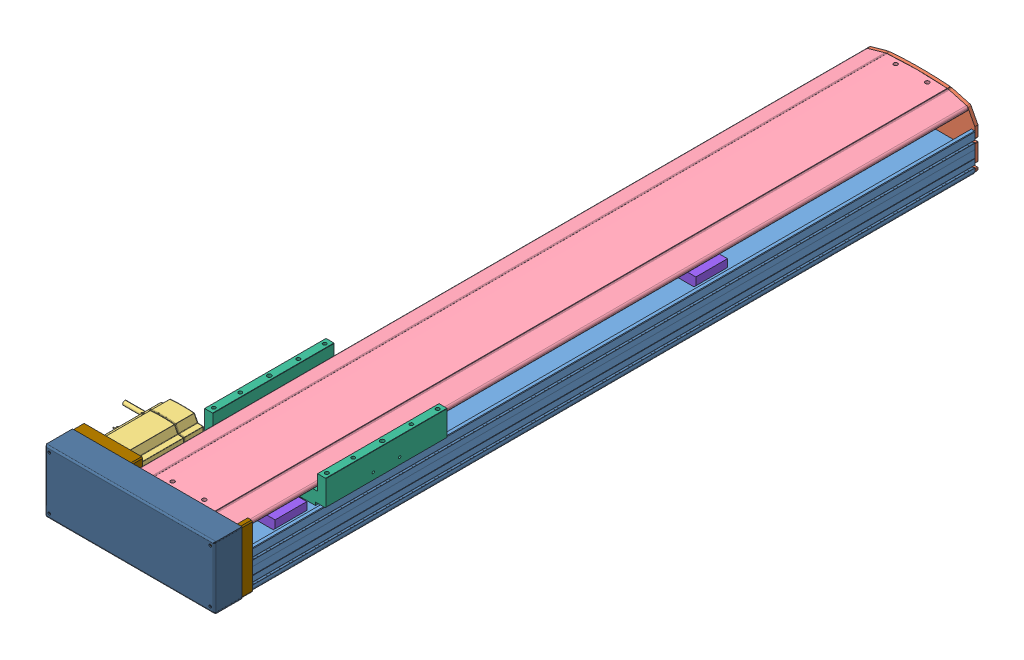
SolidWorks assembly S22M-BR-750W, configuration 默认. Lengths in mm.
Overall size (376.41 122 1448.01).
13 component instances, 10 part files, 40 mates.
Components (placement in the parent):
- S22-BL底座^S22M-BR-750W-1: S22-BL底座^S22M-BR-750W [默认] at origin size (220 71.7 1370) (virtual)
- S22-GY侧盖^S22M-BR-750W-1: S22-GY侧盖^S22M-BR-750W [默认] at (0 0 -691) size (219 117 6) (virtual)
- 750W电机^S22M-BR-750W-1: 750W电机^S22M-BR-750W [默认] at (-162.71 60.3 543) x (0 -1 0) z (0 0 1) size (82 139.7 182) (virtual)
- S22-BL上盖^S22M-BR-750W-1: S22-BL上盖^S22M-BR-750W [默认] at (0 117.9988 10) size (193.4 19.6 1390) (virtual)
- 672 传感器^S22M-BR-750W-1: 672 传感器^S22M-BR-750W [默认] at (-116.75 60.4 -424.15) x (-1 0 0) z (0 0 1) size (13.5 27.4 26.1) (virtual)
- 672 传感器^S22M-BR-750W-2: 672 传感器^S22M-BR-750W [默认] at (-116.75 60.4 444.9) x (-1 0 0) z (0 0 1) size (13.5 27.4 26.1) (virtual)
- 672 传感器^S22M-BR-750W-3: 672 传感器^S22M-BR-750W [默认] at (-116.75 60.4 418.8) x (-1 0 0) z (0 0 1) size (13.5 27.4 26.1) (virtual)
- S22-BL-SFS25滑座^S22M-BR-750W-1: S22-BL-SFS25滑座^S22M-BR-750W [默认] at (0 0.3 435) size (230 80 230) (virtual)
- 复件 外置感应片ST22^S22M-BR-750W-1: 复件 外置感应片ST22^S22M-BR-750W [Default] at (-115 64.3 435) x (0 0 -1) z (1 0 0) size (70 28 1) (virtual)
- 滑座S22M^S22M-BR-750W-1: 滑座S22M^S22M-BR-750W [Default] at (0 60.3 570) size (198 57 60) (virtual)
- 滑座S22M^S22M-BR-750W-2: 滑座S22M^S22M-BR-750W [Default] at (0 60.3 -227) size (198 57 60) (virtual)
- 电机板S22M-BR-P80^S22M-BR-750W-1: 电机板S22M-BR-P80^S22M-BR-750W [Default] at (-0.4531 120.8531 705) x (-1 0 0) z (0 0 -1) size (321 118 20) (virtual)
- 罩壳SF22-BLR^S22M-BR-750W-1: 罩壳SF22-BLR^S22M-BR-750W [Default] at (-48.71 59.8 755) size (321.24 118.01 52.01) (virtual)
Mates (geometry in assembly coordinates):
- 重合1: coincident: plane of S22-BL底座^S22M-BR-750W-1 through (0 0 0) normal (1 0 0); plane of assembly through (0 0 0) normal (1 0 0)
- 重合2: coincident: plane of S22-BL底座^S22M-BR-750W-1 through (0 0 0) normal (0 1 0); plane of assembly through (0 0 0) normal (0 1 0)
- 重合3: coincident: plane of S22-BL底座^S22M-BR-750W-1 through (0 0 0) normal (0 0 1); plane of assembly through (0 0 0) normal (0 0 1)
- 重合4: coincident: plane of S22-BL底座^S22M-BR-750W-1 through (-104.5 14 -685) normal (0 0 -1); plane of S22-GY侧盖^S22M-BR-750W-1 through (0 -619.785 -685) normal (0 0 1)
- 重合5: coincident: plane of S22-BL底座^S22M-BR-750W-1 through (0 0 0) normal (1 0 0); plane of S22-GY侧盖^S22M-BR-750W-1 through (0 0 -691) normal (1 0 0)
- 重合6: coincident: plane of S22-BL底座^S22M-BR-750W-1 through (0 0 0) normal (0 1 0); plane of S22-GY侧盖^S22M-BR-750W-1 through (0 0 -691) normal (0 1 0)
- 重合36: coincident: plane of S22-BL底座^S22M-BR-750W-1 through (0 0 0) normal (1 0 0); plane of S22-BL上盖^S22M-BR-750W-1 through (0 117.9988 10) normal (1 0 0)
- Distance3: distance = 122 mm: plane of S22-BL-SFS25滑座^S22M-BR-750W-1 through (99 122.3 550) normal (0 1 0); plane of S22-BL底座^S22M-BR-750W-1 through (110 0.3 685) normal (0 -1 0)
- Coincident5: coincident: plane of S22-BL底座^S22M-BR-750W-1 through (0 0 0) normal (1 0 0); plane of S22-BL-SFS25滑座^S22M-BR-750W-1 through (0 0.3 435) normal (1 0 0)
- Distance4: distance = 117.9988 mm: plane of S22-BL上盖^S22M-BR-750W-1 through (0 117.9988 10) normal (0 1 0); plane of S22-BL底座^S22M-BR-750W-1 through (0 0 0) normal (0 1 0)
- Coincident6: coincident: plane of 672 传感器^S22M-BR-750W-2 through (-110 71.5 451.2) normal (1 0 0); plane of 672 传感器^S22M-BR-750W-3 through (-110 71.5 425.1) normal (1 0 0)
- Coincident7: coincident: plane of 672 传感器^S22M-BR-750W-1 through (-110 71.5 -417.85) normal (1 0 0); plane of 672 传感器^S22M-BR-750W-2 through (-110 71.5 451.2) normal (1 0 0)
- Coincident8: coincident: plane of 672 传感器^S22M-BR-750W-2 through (-110 49.3 451.2) normal (0 -1 0); plane of 672 传感器^S22M-BR-750W-3 through (-110 49.3 425.1) normal (0 -1 0)
- Coincident9: coincident: plane of 672 传感器^S22M-BR-750W-1 through (-110 49.3 -417.85) normal (0 -1 0); plane of 672 传感器^S22M-BR-750W-2 through (-110 49.3 451.2) normal (0 -1 0)
- Coincident10: coincident: plane of 672 传感器^S22M-BR-750W-2 through (-113 52.5 435) normal (0 0 -1); plane of 672 传感器^S22M-BR-750W-3 through (-113 52.5 435) normal (0 0 1)
- Coincident11: coincident: plane of S22-BL底座^S22M-BR-750W-1 through (-110 42 685) normal (-1 0 0); plane of 672 传感器^S22M-BR-750W-2 through (-110 71.5 451.2) normal (1 0 0)
- Distance5: distance = 49 mm: plane of 672 传感器^S22M-BR-750W-1 through (-110 49.3 -417.85) normal (0 -1 0); plane of S22-BL底座^S22M-BR-750W-1 through (-110 0.3 685) normal (0 -1 0)
- Distance7: distance = 260.85 mm: plane of 672 传感器^S22M-BR-750W-1 through (-123.5 49.3 -424.15) normal (0 0 -1); plane of S22-BL底座^S22M-BR-750W-1 through (-104.5 14 -685) normal (0 0 -1)
- 重合152: coincident: plane of S22-BL-SFS25滑座^S22M-BR-750W-1 through (-115 122.3 550) normal (-1 0 0); plane of 复件 外置感应片ST22^S22M-BR-750W-1 through (-115 64.3 435) normal (1 0 0)
- 同心1: concentric: cylinder of S22-BL-SFS25滑座^S22M-BR-750W-1 through (-115 87.3 410) axis (-1 0 0) radius 2.1; cylinder of 复件 外置感应片ST22^S22M-BR-750W-1 through (-116 87.3 410) axis (1 0 0) radius 2.55
- 同心2: concentric: cylinder of S22-BL-SFS25滑座^S22M-BR-750W-1 through (-115 87.3 460) axis (-1 0 0) radius 2.1; cylinder of 复件 外置感应片ST22^S22M-BR-750W-1 through (-116 87.3 460) axis (1 0 0) radius 2.55
- 重合153: coincident: plane of 滑座S22M^S22M-BR-750W-1 through (-40.6202 86.3 630) normal (0 1 0); plane of 滑座S22M^S22M-BR-750W-2 through (-40.6202 86.3 -167) normal (0 1 0)
- 重合154: coincident: plane of 滑座S22M^S22M-BR-750W-1 through (-99 29.3 570) normal (-1 0 0); plane of 滑座S22M^S22M-BR-750W-2 through (-99 29.3 -227) normal (-1 0 0)
- 重合155: coincident: plane of 滑座S22M^S22M-BR-750W-2 through (0 60.3 -227) normal (1 0 0); plane of assembly through (0 0 0) normal (1 0 0)
- 距离3: distance = 86 mm: plane of 滑座S22M^S22M-BR-750W-1 through (-40.6202 86.3 630) normal (0 1 0); plane of S22-BL底座^S22M-BR-750W-1 through (-110 0.3 685) normal (0 -1 0)
- 距离4: distance: plane of 滑座S22M^S22M-BR-750W-1 through (40.6202 91.3 570) normal (0 0 -1); plane of 滑座S22M^S22M-BR-750W-2 through (40.6202 91.3 -167) normal (0 0 1)
- 距离5: distance = 20 mm: plane of S22-BL-SFS25滑座^S22M-BR-750W-1 through (0 60.3 550) normal (0 0 1); plane of 滑座S22M^S22M-BR-750W-1 through (40.6202 91.3 570) normal (0 0 -1)
- LimitDistance1: limit distance = 6 mm: line of 672 传感器^S22M-BR-750W-3 through (-113 57.6 435) axis (0 -1 0); plane of 复件 外置感应片ST22^S22M-BR-750W-1 through (-116 64.3 429) normal (0 0 -1)
- 重合156: coincident: plane of S22-BL底座^S22M-BR-750W-1 through (-104.5 14 685) normal (0 0 1); plane of 电机板S22M-BR-P80^S22M-BR-750W-1 through (-0.4531 120.8531 685) normal (0 0 -1)
- 重合157: coincident: plane of S22-BL底座^S22M-BR-750W-1 through (110 0 685) normal (1 0 0); plane of 电机板S22M-BR-P80^S22M-BR-750W-1 through (111.29 118.8 685) normal (1 0 0)
- 距离8: distance = 0.5 mm: plane of 电机板S22M-BR-P80^S22M-BR-750W-1 through (111.29 0.8 685) normal (0 -1 0); plane of S22-BL底座^S22M-BR-750W-1 through (110 0.3 685) normal (0 -1 0)
- 重合159: coincident: plane of 电机板S22M-BR-P80^S22M-BR-750W-1 through (111.29 118.8 685) normal (1 0 0); plane of 罩壳SF22-BLR^S22M-BR-750W-1 through (111.29 59.8 755) normal (1 0 0)
- 重合160: coincident: plane of 电机板S22M-BR-P80^S22M-BR-750W-1 through (-0.4531 120.8531 705) normal (0 0 1); plane of 罩壳SF22-BLR^S22M-BR-750W-1 through (-209.71 118.8 705) normal (0 0 -1)
- 重合161: coincident: plane of 电机板S22M-BR-P80^S22M-BR-750W-1 through (111.29 0.8 685) normal (0 -1 0); plane of 罩壳SF22-BLR^S22M-BR-750W-1 through (-48.71 0.8 755) normal (0 -1 0)
- 相切1: tangent: cylinder of 750W电机^S22M-BR-750W-1 through (-162.71 60.3 685) axis (0 0 1) radius 35; plane of 电机板S22M-BR-P80^S22M-BR-750W-1 through (-166.71 95.3 705.001) normal (0 -1 0)
- 重合162: coincident: plane of 750W电机^S22M-BR-750W-1 through (-162.71 60.3 685) normal (0 0 1); plane of 电机板S22M-BR-P80^S22M-BR-750W-1 through (-0.4531 120.8531 685) normal (0 0 -1)
- 距离9: distance = 7 mm: plane of 750W电机^S22M-BR-750W-1 through (-202.71 20.3 543) normal (-1 0 0); plane of 电机板S22M-BR-P80^S22M-BR-750W-1 through (-209.71 118.8 685) normal (-1 0 0)
- 距离10: distance = 322 mm: line of 672 传感器^S22M-BR-750W-3 through (-113 57.6 435) axis (0 -1 0); plane of 罩壳SF22-BLR^S22M-BR-750W-1 through (-48.71 59.8 757) normal (0 0 1)
- 重合165: coincident: plane of S22-GY侧盖^S22M-BR-750W-1 through (0 -619.785 -685) normal (0 0 1); plane of S22-BL上盖^S22M-BR-750W-1 through (59.5897 110.29 -685) normal (0 0 -1)
- 距离12: distance = 52.71 mm: cylinder of 750W电机^S22M-BR-750W-1 through (-162.71 60.3 688) axis (0 0 1) radius 9.5; plane of S22-BL底座^S22M-BR-750W-1 through (-110 0 685) normal (-1 0 0)
